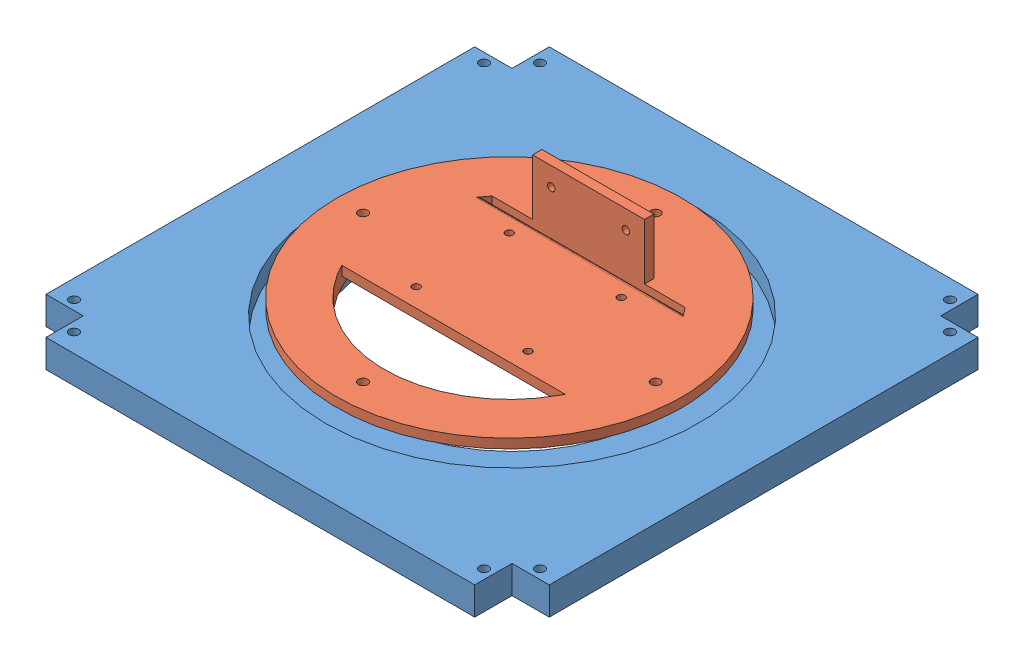
SolidWorks assembly Assem1, configuration Default. Lengths in mm.
Overall size (270 55 270).
2 component instances, 2 part files, 0 mates.
Components (placement in the parent):
- outerring-2: outerring [Default] at (-58.0711 143.1519 348.2112) size (270 15 270)
- innerringv2-2: innerringv2 [Default] at (76.8148 167.2843 214.5126) x (1 0 0) z (0 -1 0) size (185 185 55)
